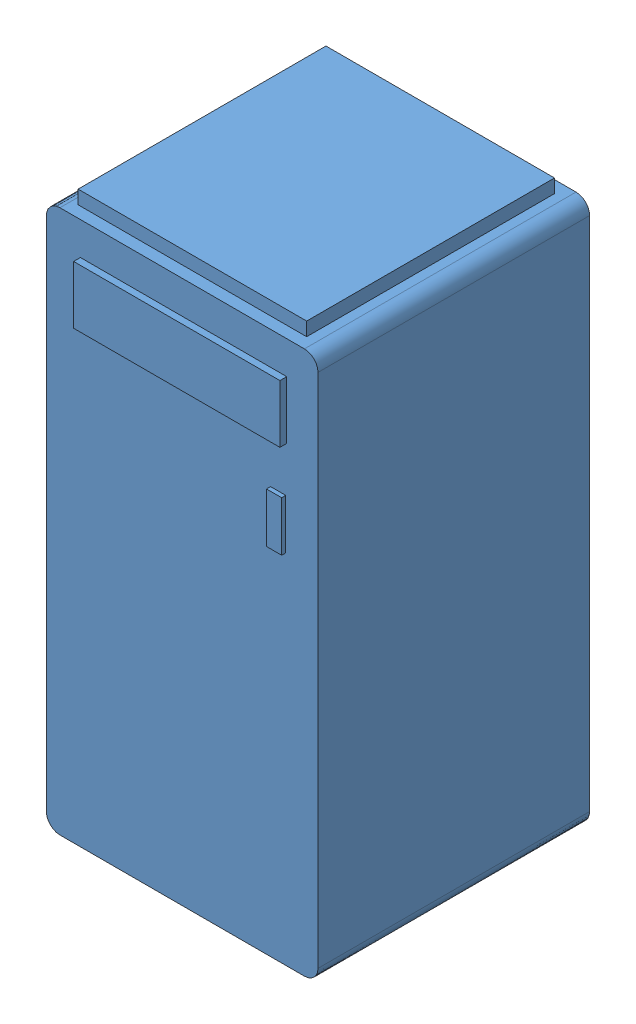
SolidWorks assembly Assem2, configuration Default. Lengths in mm.
Overall size (200 410 205).
33 component instances, 3 part files, 0 mates.
Components (placement in the parent):
- Part3-1: Part3 [Default] at (40.8308 -10.9225 195.7447) x (0 0 1) z (-1 0 0) size (205 410 200)
- Assem1-1: Assem1 [Default] at (81.7259 94.8695 -190.692) size (29.57 250 70)
  - Part1-1: Part1 [Default] at (106.4402 40.0967 246.3661) size (29.57 250 70)
  - Part2-2: Part2 [Default] at (104.457 162.9306 239.9293) x (0 -1 0) z (0 0 1) size (20 5 12)
  - Part2-3: Part2 [Default] at (110.3334 167.6266 241.004) x (0 1 0) z (0 0 1) size (20 5 12)
  - Part2-4: Part2 [Default] at (110.2168 188.947 241.162) x (0 1 0) z (0 0 1) size (20 5 12)
  - Part2-5: Part2 [Default] at (110.5749 253.441 241.5001) x (0 1 0) z (0 0 1) size (20 5 12)
  - Part2-6: Part2 [Default] at (110.2688 231.6683 241.2229) x (0 1 0) z (0 0 1) size (20 5 12)
  - Part2-7: Part2 [Default] at (110.3906 210.2139 240.9907) x (0 1 0) z (0 0 1) size (20 5 12)
- Assem1-2: Assem1 [Default] at (-63.2595 98.1149 258.135) x (0 0 -1) z (1 0 0) size (29.57 250 70)
  - Part1-1: Part1 [Default] at (106.4402 40.0967 246.3661) size (29.57 250 70)
  - Part2-2: Part2 [Default] at (104.457 162.9306 239.9293) x (0 -1 0) z (0 0 1) size (20 5 12)
  - Part2-3: Part2 [Default] at (110.3334 167.6266 241.004) x (0 1 0) z (0 0 1) size (20 5 12)
  - Part2-4: Part2 [Default] at (110.2168 188.947 241.162) x (0 1 0) z (0 0 1) size (20 5 12)
  - Part2-5: Part2 [Default] at (110.5749 253.441 241.5001) x (0 1 0) z (0 0 1) size (20 5 12)
  - Part2-6: Part2 [Default] at (110.2688 231.6683 241.2229) x (0 1 0) z (0 0 1) size (20 5 12)
  - Part2-7: Part2 [Default] at (110.3906 210.2139 240.9907) x (0 1 0) z (0 0 1) size (20 5 12)
- Assem1-3: Assem1 [Default] at (-16.4464 98.0758 -105.781) size (29.57 250 70)
  - Part1-1: Part1 [Default] at (106.4402 40.0967 246.3661) size (29.57 250 70)
  - Part2-2: Part2 [Default] at (104.457 162.9306 239.9293) x (0 -1 0) z (0 0 1) size (20 5 12)
  - Part2-3: Part2 [Default] at (110.3334 167.6266 241.004) x (0 1 0) z (0 0 1) size (20 5 12)
  - Part2-4: Part2 [Default] at (110.2168 188.947 241.162) x (0 1 0) z (0 0 1) size (20 5 12)
  - Part2-5: Part2 [Default] at (110.5749 253.441 241.5001) x (0 1 0) z (0 0 1) size (20 5 12)
  - Part2-6: Part2 [Default] at (110.2688 231.6683 241.2229) x (0 1 0) z (0 0 1) size (20 5 12)
  - Part2-7: Part2 [Default] at (110.3906 210.2139 240.9907) x (0 1 0) z (0 0 1) size (20 5 12)
- Assem1-4: Assem1 [Default] at (-147.1594 93.0991 155.8287) x (0 0 -1) z (1 0 0) size (29.57 250 70)
  - Part1-1: Part1 [Default] at (106.4402 40.0967 246.3661) size (29.57 250 70)
  - Part2-2: Part2 [Default] at (104.457 162.9306 239.9293) x (0 -1 0) z (0 0 1) size (20 5 12)
  - Part2-3: Part2 [Default] at (110.3334 167.6266 241.004) x (0 1 0) z (0 0 1) size (20 5 12)
  - Part2-4: Part2 [Default] at (110.2168 188.947 241.162) x (0 1 0) z (0 0 1) size (20 5 12)
  - Part2-5: Part2 [Default] at (110.5749 253.441 241.5001) x (0 1 0) z (0 0 1) size (20 5 12)
  - Part2-6: Part2 [Default] at (110.2688 231.6683 241.2229) x (0 1 0) z (0 0 1) size (20 5 12)
  - Part2-7: Part2 [Default] at (110.3906 210.2139 240.9907) x (0 1 0) z (0 0 1) size (20 5 12)
